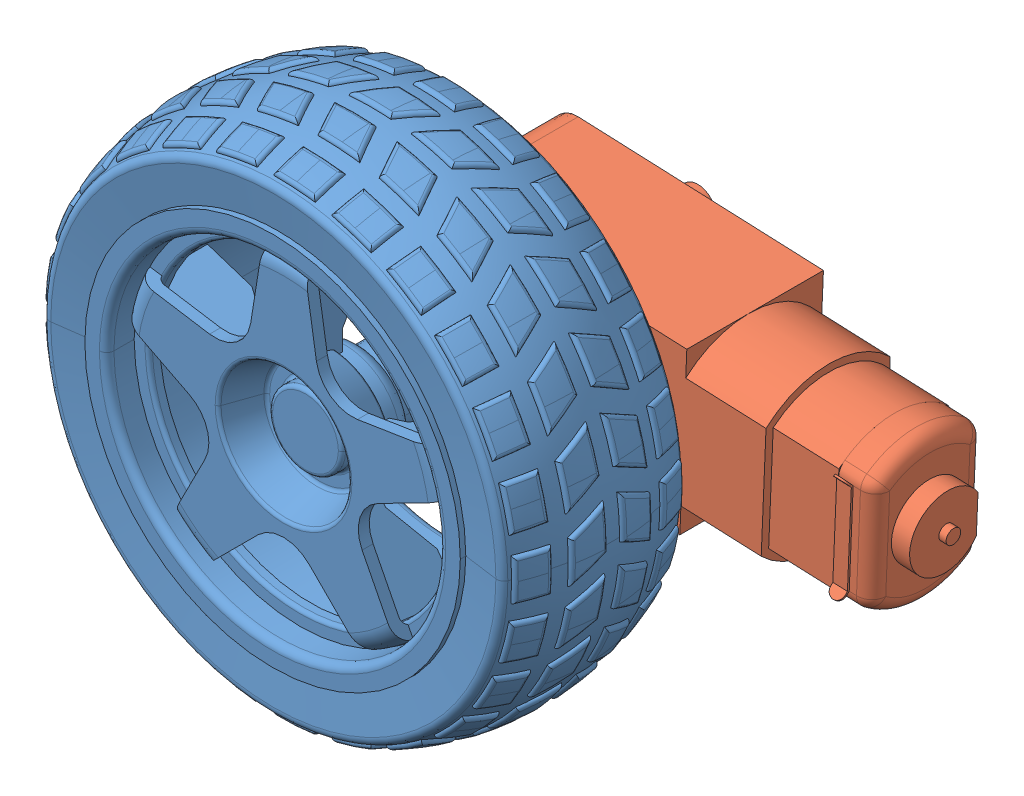
SolidWorks assembly ensemble roue, configuration Default. Lengths in mm.
Overall size (89.53 69.08 58.2).
2 component instances, 2 part files, 2 mates.
Components (placement in the parent):
- Wheel D65x25-1: Wheel D65x25 [Default] at (-64.7956 10.9879 41.7655) size (69.1 69.08 30)
- Arduino Gear Motor-1: Arduino Gear Motor [Default] at (-75.7856 11.455 2.1655) x (0 0 1) z (-0.999098 0.042468 0) size (37.2 22.5 65.5)
Mates (geometry in assembly coordinates):
- Concentric1: concentric: cylinder of Wheel D65x25-1 through (-64.7956 10.9879 41.7655) axis (0 0 1) radius 2.75; cylinder of Arduino Gear Motor-1 through (-64.7956 10.9879 11.7655) axis (0 0 1) radius 2.5
- Coincident1: coincident: plane of Wheel D65x25-1 through (-64.7956 10.9879 11.7655) normal (0 0 -1); plane of Arduino Gear Motor-1 through (-64.7956 10.9879 11.7655) normal (0 0 1)
